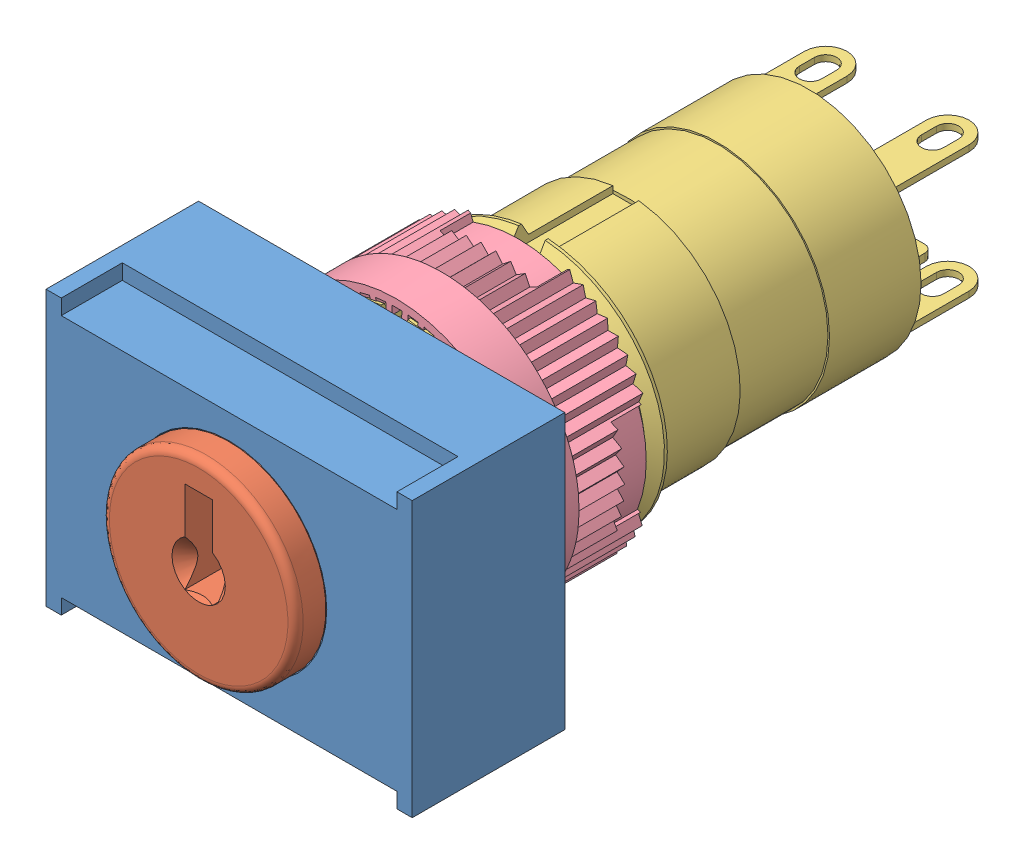
SolidWorks assembly Key Switch ADP16K4-ATO-1A, configuration Default. Lengths in mm.
Overall size (24 18.12 46.69).
4 component instances, 4 part files, 8 mates.
Components (placement in the parent):
- KeySwitch16_Part1-1: KeySwitch16_Part1 [Default] at (0 0 28) x (-1 0 0) z (0 1 0) size (24 10 18)
- KeySwitch16_Part2-1: KeySwitch16_Part2 [Default] at (0 0 38) x (0 -1 0) z (-1 0 0) size (12.7 25.69 12.7)
- KeySwitch16_Part3-1: KeySwitch16_Part3 [Default] at origin size (16.63 16.61 34.92)
- KeySwitch16_Part4-1: KeySwitch16_Part4 [Default] at (0 0 27.0607) x (0.999976 -0.006869 0) z (0 0 -1) size (18 18 8)
Mates (geometry in assembly coordinates):
- Concentric1: concentric anti-aligned: cylinder of KeySwitch16_Part1-1 through (0 0 38) axis (0 0 -1) radius 6.4; cylinder of KeySwitch16_Part2-1 through (0 0 14.5) axis (0 0 1) radius 5.5
- Coincident1: coincident anti-aligned: plane of KeySwitch16_Part1-1 through (0 0 38) normal (0 0 1); plane of KeySwitch16_Part2-1 through (0 -6.35 38) normal (0 0 -1)
- Perpendicular1: perpendicular: plane of KeySwitch16_Part1-1 through (0 0 28) normal (-1 0 0); plane of KeySwitch16_Part2-1 through (0 0 38) normal (0 -1 0)
- Concentric2: concentric aligned: cylinder of KeySwitch16_Part2-1 through (0 0 14.5) axis (0 0 1) radius 5.5; cylinder of KeySwitch16_Part3-1 through (0 0 8) axis (0 0 1) radius 6.5
- Coincident2: coincident anti-aligned: plane of KeySwitch16_Part1-1 through (0 0 28) normal (0 0 -1); plane of KeySwitch16_Part3-1 through (0 0 28) normal (0 0 1)
- Coincident3: coincident aligned: plane of KeySwitch16_Part1-1 through (0 0 28) normal (0 1 0); plane of KeySwitch16_Part3-1 through (0 0 0) normal (0 1 0)
- Screw1: screw = 1 anti-aligned: cylinder of KeySwitch16_Part3-1 through (0 0 28) axis (0 0 -1) radius 7.5; cylinder of KeySwitch16_Part4-1 through (0 0 19.0607) axis (0 0 1) radius 7.5
- Coincident4: coordinate: point of KeySwitch16_Part3-1; point of assembly
